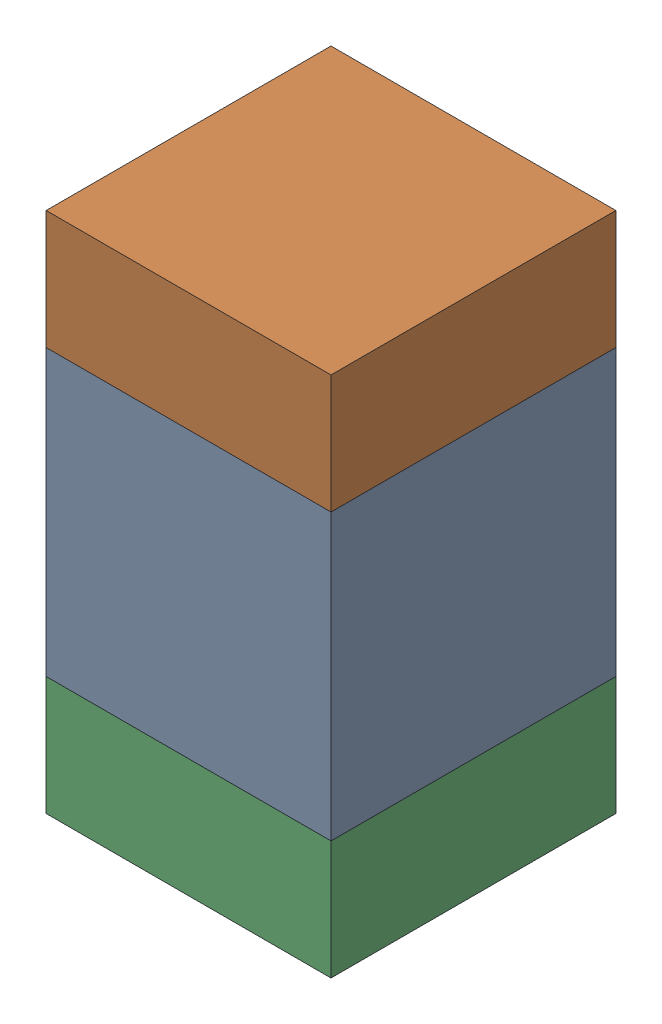
SolidWorks assembly C124_2PCB, configuration Default. Lengths in mm.
Overall size (0.6 1.1 0.6).
6 component instances, 2 part files, 0 mates.
Components (placement in the parent):
- 761606048-1: 761606048 [Default] at (105.3 99.7 0) size (0.6 0.6 0.6)
  - Extruded_9-1: Extruded_9 [Default] at origin size (0.6 0.6 0.6)
- 854785296-1: 854785296 [Default] at (105.3 100.125 0) size (0.6 0.25 0.6)
  - Extruded_10-1: Extruded_10 [Default] at origin size (0.6 0.25 0.6)
- 854785296-2: 854785296 [Default] at (105.3 99.275 0) size (0.6 0.25 0.6)
  - Extruded_10-1: Extruded_10 [Default] at origin size (0.6 0.25 0.6)
